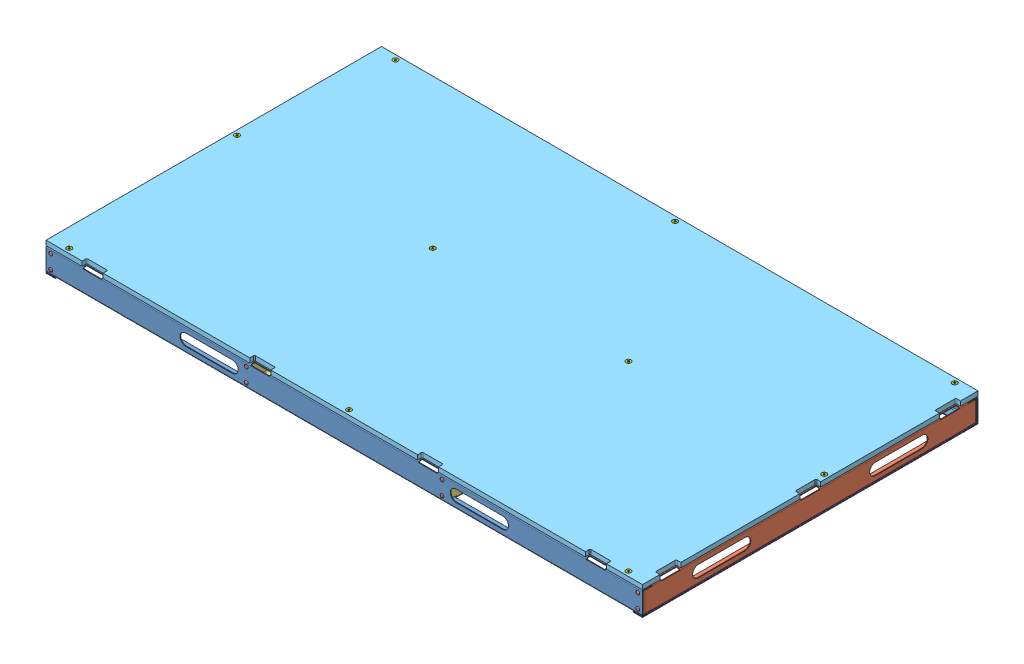
SolidWorks assembly GE-19051, configuration Default. Lengths in mm.
Overall size (1625.6 77.99 917.59).
46 component instances, 8 part files, 49 mates.
Components (placement in the parent):
- GE-19063-1: GE-19063 [Default] at origin size (1625.6 63.5 917.59)
  - GE-19066-2: GE-19066 [Default] at (812.8 0 -457.2) x (0 0 -1) z (1 0 0) size (25.4 63.5 1625.6)
  - GE-19064-2: GE-19064 [Default] at (-812.8 0 -430.5376) x (-1 0 0) z (0 0 -1) size (25.4 63.5 910.59)
  - GE-19064-3: GE-19064 [Default] at (812.8 0 430.5224) size (25.4 63.5 910.59)
  - GE-19066-3: GE-19066 [Default] at (-812.8 0 457.1848) x (0 0 1) z (-1 0 0) size (25.4 63.5 1625.6)
  - GE-19065-1: GE-19065 [Default] at (279.4 0 -0.0076) size (25.4 63.5 910.59)
  - GE-19065-2: GE-19065 [Default] at (-279.4 63.5 -0.0076) x (-1 0 0) z (0 0 1) size (25.4 63.5 910.59)
  - rivet_.1875_.126-.25-2: rivet_.1875_.126-.25 [Default] at (-800.1 50.8 457.1848) size (10.01 10.01 13.03)
  - rivet_.1875_.126-.25-10: rivet_.1875_.126-.25 [Default] at (-266.7 50.8 457.1848) x (0.959125 0.282984 0) z (0 0 1) size (10.01 10.01 13.03)
  - rivet_.1875_.126-.25-11: rivet_.1875_.126-.25 [Default] at (-266.7 12.7 457.1848) x (0.928571 0.371154 0) z (0 0 1) size (10.01 10.01 13.03)
  - rivet_.1875_.126-.25-12: rivet_.1875_.126-.25 [Default] at (266.7 50.8 457.1848) x (0.906989 0.421154 0) z (0 0 1) size (10.01 10.01 13.03)
  - rivet_.1875_.126-.25-13: rivet_.1875_.126-.25 [Default] at (266.7 12.7 457.1848) x (0.902849 0.429957 0) z (0 0 1) size (10.01 10.01 13.03)
  - rivet_.1875_.126-.25-14: rivet_.1875_.126-.25 [Default] at (800.1 50.8 457.1848) x (0.919615 0.39282 0) z (0 0 1) size (10.01 10.01 13.03)
  - rivet_.1875_.126-.25-15: rivet_.1875_.126-.25 [Default] at (800.1 12.7 457.1848) x (0.952324 0.305088 0) z (0 0 1) size (10.01 10.01 13.03)
  - rivet_.1875_.126-.25-18: rivet_.1875_.126-.25 [Default] at (-800.1 12.7 457.1848) x (0.987351 0.158553 0) z (0 0 1) size (10.01 10.01 13.03)
  - rivet_.1875_.126-.25-20: rivet_.1875_.126-.25 [Default] at (800.1 50.8 -457.2) x (1 0 0) z (0 0 -1) size (10.01 10.01 13.03)
  - rivet_.1875_.126-.25-21: rivet_.1875_.126-.25 [Default] at (800.1 12.7 -457.2) x (0.987351 0.158553 0) z (0 0 -1) size (10.01 10.01 13.03)
  - rivet_.1875_.126-.25-22: rivet_.1875_.126-.25 [Default] at (266.7 50.8 -457.2) x (0.959125 0.282984 0) z (0 0 -1) size (10.01 10.01 13.03)
  - rivet_.1875_.126-.25-23: rivet_.1875_.126-.25 [Default] at (266.7 12.7 -457.2) x (0.928571 0.371154 0) z (0 0 -1) size (10.01 10.01 13.03)
  - rivet_.1875_.126-.25-24: rivet_.1875_.126-.25 [Default] at (-266.7 50.8 -457.2) x (0.906989 0.421154 0) z (0 0 -1) size (10.01 10.01 13.03)
  - rivet_.1875_.126-.25-25: rivet_.1875_.126-.25 [Default] at (-266.7 12.7 -457.2) x (0.902849 0.429957 0) z (0 0 -1) size (10.01 10.01 13.03)
  - rivet_.1875_.126-.25-26: rivet_.1875_.126-.25 [Default] at (-800.1 50.8 -457.2) x (0.919615 0.39282 0) z (0 0 -1) size (10.01 10.01 13.03)
  - rivet_.1875_.126-.25-27: rivet_.1875_.126-.25 [Default] at (-800.1 12.7 -457.2) x (0.952324 0.305088 0) z (0 0 -1) size (10.01 10.01 13.03)
- GE-19052-1: GE-19052 [Default] at (-812.8 63.5 457.2) size (1625.6 12.7 914.4)
- nylock_.25_20-1: nylock_.25_20 [Default] at (-762 61.6026 444.4848) x (-1 0 0) z (0 0 1) size (11.11 7.94 12.83)
- nylock_.25_20-2: nylock_.25_20 [Default] at (0 61.6026 444.4848) x (-0.982082 0 0.188455) z (0.188455 0 0.982082) size (11.11 7.94 12.83)
- nylock_.25_20-3: nylock_.25_20 [Default] at (762 61.6026 444.4848) x (-0.918365 0 0.395734) z (0.395734 0 0.918365) size (11.11 7.94 12.83)
- nylock_.25_20-4: nylock_.25_20 [Default] at (800.1 61.6026 -50.8076) x (-0.8 0 0.6) z (0.6 0 0.8) size (11.11 7.94 12.83)
- nylock_.25_20-5: nylock_.25_20 [Default] at (266.7 61.6026 -50.8076) x (-0.63358 0 0.773678) z (0.773678 0 0.63358) size (11.11 7.94 12.83)
- nylock_.25_20-8: nylock_.25_20 [Default] at (-800.1 61.6026 -50.8076) x (0.999877 0 -0.015704) z (-0.015704 0 -0.999877) size (11.11 7.94 12.83)
- nylock_.25_20-9: nylock_.25_20 [Default] at (-762 61.6026 -444.5) x (-0.263225 0 0.964735) z (0.964735 0 0.263225) size (11.11 7.94 12.83)
- nylock_.25_20-10: nylock_.25_20 [Default] at (0 61.6026 -444.5) x (-0.120178 0 0.992752) z (0.992752 0 0.120178) size (11.11 7.94 12.83)
- nylock_.25_20-11: nylock_.25_20 [Default] at (762 61.6026 -444.5) x (-0.030377 0 0.999538) z (0.999538 0 0.030377) size (11.11 7.94 12.83)
- nylock_.25_20-12: nylock_.25_20 [Default] at (-266.7 61.6026 -50.8076) x (0.546944 0 0.837169) z (0.837169 0 -0.546944) size (11.11 7.94 12.83)
- flat_hex_.25_20_1-1: flat_hex_.25_20_1 [91253A542] at (762 76.2 -444.5) x (1 0 0) z (0 1 0) size (13.49 13.49 25.61)
- flat_hex_.25_20_1-2: flat_hex_.25_20_1 [91253A542] at (0 76.2 -444.5) x (0.982082 0 -0.188455) z (0 1 0) size (13.49 13.49 25.61)
- flat_hex_.25_20_1-3: flat_hex_.25_20_1 [91253A542] at (-762 76.2 -444.5) x (0.918365 0 -0.395734) z (0 1 0) size (13.49 13.49 25.61)
- flat_hex_.25_20_1-4: flat_hex_.25_20_1 [91253A542] at (-800.1 76.2 -50.8) x (0.8 0 -0.6) z (0 1 0) size (13.49 13.49 25.61)
- flat_hex_.25_20_1-5: flat_hex_.25_20_1 [91253A542] at (-762 76.2 444.5) x (0.63358 0 -0.773678) z (0 1 0) size (13.49 13.49 25.61)
- flat_hex_.25_20_1-6: flat_hex_.25_20_1 [91253A542] at (0 76.2 444.5) x (0.443629 0 -0.896211) z (0 1 0) size (13.49 13.49 25.61)
- flat_hex_.25_20_1-7: flat_hex_.25_20_1 [91253A542] at (-266.7 76.2 -50.8) x (0.263225 0 -0.964735) z (0 1 0) size (13.49 13.49 25.61)
- flat_hex_.25_20_1-8: flat_hex_.25_20_1 [91253A542] at (266.7 76.2 -50.8) x (0.120178 0 -0.992752) z (0 1 0) size (13.49 13.49 25.61)
- flat_hex_.25_20_1-9: flat_hex_.25_20_1 [91253A542] at (762 76.2 444.5) x (0.030377 0 -0.999538) z (0 1 0) size (13.49 13.49 25.61)
- flat_hex_.25_20_1-10: flat_hex_.25_20_1 [91253A542] at (800.1 76.2 -50.8) x (0 0 -1) z (0 1 0) size (13.49 13.49 25.61)
- Hook_1_36-1: Hook_1_36 [Default] at (-787.4 -1.5875 457.2) x (0 0 -1) z (1 0 0) size (914.4 1.59 25.4)
- Hook_1_36-2: Hook_1_36 [Default] at (787.4 -1.5875 -457.2) x (0 0 1) z (-1 0 0) size (914.4 1.59 25.4)
Mates (geometry in assembly coordinates):
- Coincident1: coincident: plane of GE-19063-1/GE-19064-3 through (812.8 63.5 430.5224) normal (0 1 0); plane of GE-19052-1 through (-812.8 63.5 457.2) normal (0 -1 0)
- Concentric1: concentric: cylinder of GE-19063-1/GE-19066-2 through (0 61.6026 -444.5) axis (0 1 0) radius 3.3655; cylinder of GE-19052-1 through (0 76.2 -444.5) axis (0 1 0) radius 3.5712
- Concentric2: concentric: cylinder of GE-19063-1/GE-19066-2 through (-762 61.6026 -444.5) axis (0 1 0) radius 3.3655; cylinder of GE-19052-1 through (-762 76.2 -444.5) axis (0 1 0) radius 3.5712
- Concentric3: concentric: cylinder of GE-19063-1/GE-19066-3 through (-762 61.6026 444.4848) axis (0 1 0) radius 3.3655; cylinder of nylock_.25_20-1 through (-762 61.6026 444.4848) axis (0 -1 0) radius 3.175
- Coincident2: coincident: plane of GE-19063-1/GE-19066-3 through (-812.8 61.6026 457.1848) normal (0 -1 0); plane of nylock_.25_20-1 through (-762 61.6026 444.4848) normal (0 1 0)
- Concentric4: concentric: cylinder of GE-19063-1/GE-19066-3 through (0 61.6026 444.4848) axis (0 1 0) radius 3.3655; cylinder of nylock_.25_20-2 through (0 61.6026 444.4848) axis (0 -1 0) radius 3.175
- Coincident4: coincident: plane of GE-19063-1/GE-19066-3 through (-812.8 61.6026 457.1848) normal (0 -1 0); plane of nylock_.25_20-2 through (0 61.6026 444.4848) normal (0 1 0)
- Coincident5: coincident: plane of GE-19063-1/GE-19066-3 through (-812.8 61.6026 457.1848) normal (0 -1 0); plane of nylock_.25_20-3 through (762 61.6026 444.4848) normal (0 1 0)
- Concentric5: concentric: cylinder of GE-19063-1/GE-19066-3 through (762 61.6026 444.4848) axis (0 1 0) radius 3.3655; cylinder of nylock_.25_20-3 through (762 61.6026 444.4848) axis (0 -1 0) radius 3.175
- Coincident6: coincident: plane of GE-19063-1/GE-19066-3 through (-812.8 61.6026 457.1848) normal (0 -1 0); plane of nylock_.25_20-4 through (800.1 61.6026 -50.8076) normal (0 1 0)
- Concentric6: concentric: cylinder of GE-19063-1/GE-19064-3 through (800.1 61.6026 -50.8076) axis (0 1 0) radius 3.3655; cylinder of nylock_.25_20-4 through (800.1 61.6026 -50.8076) axis (0 -1 0) radius 3.175
- Coincident7: coincident: plane of GE-19063-1/GE-19066-3 through (-812.8 61.6026 457.1848) normal (0 -1 0); plane of nylock_.25_20-5 through (266.7 61.6026 -50.8076) normal (0 1 0)
- Concentric7: concentric: cylinder of GE-19063-1/GE-19065-1 through (266.7 0 -50.8076) axis (0 1 0) radius 3.3655; cylinder of nylock_.25_20-5 through (266.7 61.6026 -50.8076) axis (0 -1 0) radius 3.175
- Concentric9: concentric: cylinder of GE-19063-1/GE-19064-2 through (-800.1 61.6026 -50.8076) axis (0 1 0) radius 3.3655; cylinder of nylock_.25_20-8 through (-800.1 61.6026 -50.8076) axis (0 -1 0) radius 3.175
- Coincident11: coincident: plane of GE-19063-1/GE-19066-3 through (-812.8 61.6026 457.1848) normal (0 -1 0); plane of nylock_.25_20-8 through (-800.1 61.6026 -50.8076) normal (0 1 0)
- Coincident12: coincident: plane of GE-19063-1/GE-19066-3 through (-812.8 61.6026 457.1848) normal (0 -1 0); plane of nylock_.25_20-9 through (-762 61.6026 -444.5) normal (0 1 0)
- Concentric10: concentric: cylinder of GE-19063-1/GE-19066-2 through (-762 61.6026 -444.5) axis (0 1 0) radius 3.3655; cylinder of nylock_.25_20-9 through (-762 61.6026 -444.5) axis (0 -1 0) radius 3.175
- Coincident13: coincident: plane of GE-19063-1/GE-19066-3 through (-812.8 61.6026 457.1848) normal (0 -1 0); plane of nylock_.25_20-10 through (0 61.6026 -444.5) normal (0 1 0)
- Concentric11: concentric: cylinder of GE-19063-1/GE-19066-2 through (0 61.6026 -444.5) axis (0 1 0) radius 3.3655; cylinder of nylock_.25_20-10 through (0 61.6026 -444.5) axis (0 -1 0) radius 3.175
- Coincident14: coincident: plane of GE-19063-1/GE-19066-3 through (-812.8 61.6026 457.1848) normal (0 -1 0); plane of nylock_.25_20-11 through (762 61.6026 -444.5) normal (0 1 0)
- Concentric12: concentric: cylinder of GE-19063-1/GE-19066-2 through (762 61.6026 -444.5) axis (0 1 0) radius 3.3655; cylinder of nylock_.25_20-11 through (762 61.6026 -444.5) axis (0 -1 0) radius 3.175
- Coincident15: coincident: plane of GE-19063-1/GE-19066-3 through (-812.8 61.6026 457.1848) normal (0 -1 0); plane of nylock_.25_20-12 through (-266.7 61.6026 -50.8076) normal (0 1 0)
- Concentric13: concentric: cylinder of GE-19063-1/GE-19065-2 through (-266.7 63.5 -50.8076) axis (0 -1 0) radius 3.3655; cylinder of nylock_.25_20-12 through (-266.7 61.6026 -50.8076) axis (0 -1 0) radius 3.175
- Concentric14: concentric: cylinder of assembly; cylinder of assembly; cylinder of GE-19052-1 through (762 76.2 -444.5) axis (0 1 0) radius 3.5712; cylinder of flat_hex_.25_20_1-1 through (762 50.8 -444.5) axis (0 -1 0) radius 3.175
- Coincident17: coincident: plane of assembly; plane of assembly; plane of GE-19052-1 through (-812.8 76.2 457.2) normal (0 1 0); plane of flat_hex_.25_20_1-1 through (762 76.2 -441.325) normal (0 1 0)
- Concentric15: concentric: cylinder of assembly; cylinder of assembly; cylinder of GE-19052-1 through (0 76.2 -444.5) axis (0 1 0) radius 3.5712; cylinder of flat_hex_.25_20_1-2 through (0 50.8 -444.5) axis (0 -1 0) radius 3.175
- Coincident19: coincident: plane of assembly; plane of assembly; plane of GE-19052-1 through (-812.8 76.2 457.2) normal (0 1 0); plane of flat_hex_.25_20_1-2 through (0.5983 76.2 -441.3819) normal (0 1 0)
- Coincident20: coincident: plane of assembly; plane of assembly; plane of GE-19052-1 through (-812.8 76.2 457.2) normal (0 1 0); plane of flat_hex_.25_20_1-3 through (-760.7435 76.2 -441.5842) normal (0 1 0)
- Concentric16: concentric: cylinder of assembly; cylinder of assembly; cylinder of GE-19052-1 through (-762 76.2 -444.5) axis (0 1 0) radius 3.5712; cylinder of flat_hex_.25_20_1-3 through (-762 50.8 -444.5) axis (0 -1 0) radius 3.175
- Coincident21: coincident: plane of assembly; plane of assembly; plane of GE-19052-1 through (-812.8 76.2 457.2) normal (0 1 0); plane of flat_hex_.25_20_1-4 through (-798.195 76.2 -48.26) normal (0 1 0)
- Concentric17: concentric: cylinder of assembly; cylinder of assembly; cylinder of GE-19052-1 through (-800.1 76.2 -50.8) axis (0 1 0) radius 3.5712; cylinder of flat_hex_.25_20_1-4 through (-800.1 50.8 -50.8) axis (0 -1 0) radius 3.175
- Coincident22: coincident: plane of assembly; plane of assembly; plane of GE-19052-1 through (-812.8 76.2 457.2) normal (0 1 0); plane of flat_hex_.25_20_1-5 through (-759.5436 76.2 446.5116) normal (0 1 0)
- Concentric18: concentric: cylinder of assembly; cylinder of assembly; cylinder of GE-19052-1 through (-762 76.2 444.5) axis (0 1 0) radius 3.5712; cylinder of flat_hex_.25_20_1-5 through (-762 50.8 444.5) axis (0 -1 0) radius 3.175
- Coincident23: coincident: plane of assembly; plane of assembly; plane of GE-19052-1 through (-812.8 76.2 457.2) normal (0 1 0); plane of flat_hex_.25_20_1-6 through (2.8455 76.2 445.9085) normal (0 1 0)
- Concentric19: concentric: cylinder of assembly; cylinder of assembly; cylinder of GE-19052-1 through (0 76.2 444.5) axis (0 1 0) radius 3.5712; cylinder of flat_hex_.25_20_1-6 through (0 50.8 444.5) axis (0 -1 0) radius 3.175
- Coincident24: coincident: plane of assembly; plane of assembly; plane of GE-19052-1 through (-812.8 76.2 457.2) normal (0 1 0); plane of flat_hex_.25_20_1-7 through (-263.637 76.2 -49.9643) normal (0 1 0)
- Concentric20: concentric: cylinder of assembly; cylinder of assembly; cylinder of GE-19052-1 through (-266.7 76.2 -50.8) axis (0 1 0) radius 3.5712; cylinder of flat_hex_.25_20_1-7 through (-266.7 50.8 -50.8) axis (0 -1 0) radius 3.175
- Coincident25: coincident: plane of assembly; plane of assembly; plane of GE-19052-1 through (-812.8 76.2 457.2) normal (0 1 0); plane of flat_hex_.25_20_1-8 through (269.852 76.2 -50.4184) normal (0 1 0)
- Concentric21: concentric: cylinder of assembly; cylinder of assembly; cylinder of GE-19052-1 through (266.7 76.2 -50.8) axis (0 1 0) radius 3.5712; cylinder of flat_hex_.25_20_1-8 through (266.7 50.8 -50.8) axis (0 -1 0) radius 3.175
- Coincident26: coincident: plane of assembly; plane of assembly; plane of GE-19052-1 through (-812.8 76.2 457.2) normal (0 1 0); plane of flat_hex_.25_20_1-9 through (765.1735 76.2 444.5964) normal (0 1 0)
- Concentric22: concentric: cylinder of assembly; cylinder of assembly; cylinder of GE-19052-1 through (762 76.2 444.5) axis (0 1 0) radius 3.5712; cylinder of flat_hex_.25_20_1-9 through (762 50.8 444.5) axis (0 -1 0) radius 3.175
- Coincident27: coincident: plane of assembly; plane of assembly; plane of GE-19052-1 through (-812.8 76.2 457.2) normal (0 1 0); plane of flat_hex_.25_20_1-10 through (803.275 76.2 -50.8) normal (0 1 0)
- Concentric23: concentric: cylinder of assembly; cylinder of assembly; cylinder of GE-19052-1 through (800.1 76.2 -50.8) axis (0 1 0) radius 3.5712; cylinder of flat_hex_.25_20_1-10 through (800.1 50.8 -50.8) axis (0 -1 0) radius 3.175
- Coincident28: coincident: plane of GE-19063-1/GE-19064-2 through (-812.8 0 -430.5376) normal (0 -1 0); plane of Hook_1_36-1 through (-787.4 0 457.2) normal (0 1 0)
- Coincident29: coincident: plane of GE-19063-1/GE-19066-2 through (812.8 0 -457.2) normal (0 0 -1); plane of Hook_1_36-1 through (-787.4 0 -457.2) normal (0 0 -1)
- Coincident30: coincident: plane of GE-19063-1/GE-19064-2 through (-787.4 0 430.5224) normal (1 0 0); plane of Hook_1_36-1 through (-787.4 0 457.2) normal (1 0 0)
- Coincident31: coincident: plane of GE-19063-1/GE-19064-3 through (812.8 0 430.5224) normal (0 -1 0); plane of Hook_1_36-2 through (787.4 0 -457.2) normal (0 1 0)
- Coincident32: coincident: plane of GE-19063-1/GE-19066-2 through (812.8 0 -457.2) normal (0 0 -1); plane of Hook_1_36-2 through (787.4 0 -457.2) normal (0 0 -1)
- Coincident33: coincident: plane of GE-19063-1/GE-19064-3 through (787.4 0 -430.5376) normal (-1 0 0); plane of Hook_1_36-2 through (787.4 0 -457.2) normal (-1 0 0)
